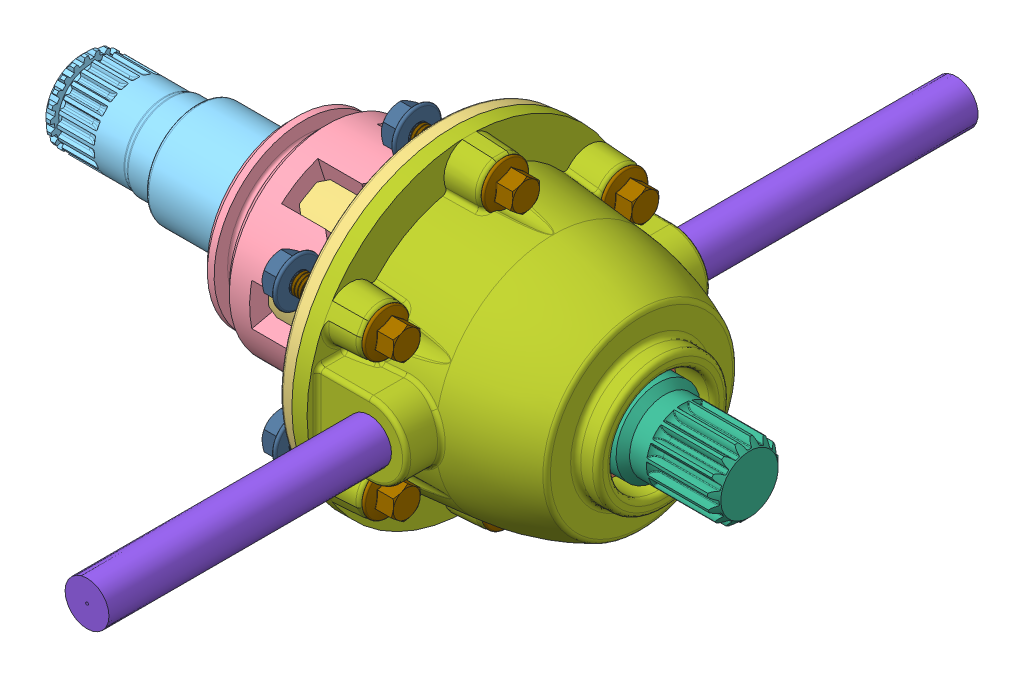
SolidWorks assembly complex assembly, configuration Default. Lengths in mm.
Overall size (197.45 149.08 257.22).
21 component instances, 10 part files, 47 mates.
Components (placement in the parent):
- gear-1: gear [Default] at (-34.573 11.9911 30.9445) x (1 0 0) z (0 0.244555 -0.969635) size (21.1 57.99 58.19)
- part 5c-1: part 5c [Default] at (51 0 0) x (0 -0.109301 0.994009) z (-1 0 0) size (44 44 5.35)
- Part6c-1: Part6c [Default] at (3.5 0.75 0) x (-1 0 0) z (0 -0.866025 -0.5) size (36 94 94)
- Part 1c-1: Part 1c [Default] at (-31.5 0.75 0) x (0 -0.477358 -0.878709) z (0 -0.878709 0.477358) size (58 34 58)
- part 3c-1: part 3c [Default] at (6.4991 0.75 0) x (-1 0 0) z (0 -0.038529 -0.999257) size (116.5 32 32)
- part 4-1: part 4 [Default] at (75.223 20.9631 25.3865) x (-1 0 0) z (0 -0.959651 -0.281194) size (58.1 57.76 58.19)
- complex-1: complex [Default] at origin size (62 133.62 96)
- straight miter gear_am-6: straight miter gear_am [Metric - Straight miter gear 2.75M12T 14.5PA 8FW ---12O13H120MD0.8N] at (20 0 28) x (0 0 -1) z (0.966628 0.256183 0) size (110.64 36.66 36.66)
- straight miter gear_am-7: straight miter gear_am [Metric - Straight miter gear 2.75M12T 14.5PA 8FW ---12O13H120MD0.8N] at (20 0 -28) x (0 0 1) z (-0.142818 0.989749 0) size (110.64 36.66 36.66)
- hex flange bolt small_iso-3: hex flange bolt small_iso [ISO 4162 - M6 x 25 x 25-S] at (21.3 -20.375 35.2905) x (-1 0 0) z (0 0.924225 0.381849) size (31.8 13.6 13.6)
- hex flange bolt small_iso-7: hex flange bolt small_iso [ISO 4162 - M6 x 25 x 25-S] at (21.3 40.75 0) x (-1 0 0) z (0 0.924225 0.381849) size (31.8 13.6 13.6)
- hex flange bolt small_iso-8: hex flange bolt small_iso [ISO 4162 - M6 x 25 x 25-S] at (21.3 20.375 -35.2905) x (-1 0 0) z (0 0.924225 0.381849) size (31.8 13.6 13.6)
- hex flange bolt small_iso-5: hex flange bolt small_iso [ISO 4162 - M6 x 25 x 25-S] at (21.3 -20.375 -35.2905) x (-1 0 0) z (0 0.924225 0.381849) size (31.8 13.6 13.6)
- hex flange bolt small_iso-2: hex flange bolt small_iso [ISO 4162 - M6 x 25 x 25-S] at (21.3 -40.75 0) x (-1 0 0) z (0 0.924225 0.381849) size (31.8 13.6 13.6)
- hex flange bolt small_iso-6: hex flange bolt small_iso [ISO 4162 - M6 x 25 x 25-S] at (21.3 20.375 35.2905) x (-1 0 0) z (0 0.924225 0.381849) size (31.8 13.6 13.6)
- hex flange nut gradea_iso-2: hex flange nut gradea_iso [ISO - 4161 - M6 - S] at (-16.5 20.375 35.2905) x (0 0 1) z (-1 0 0) size (14.2 14.2 6)
- hex flange nut gradea_iso-3: hex flange nut gradea_iso [ISO - 4161 - M6 - S] at (-16.5 40.75 0) x (0 0 1) z (-1 0 0) size (14.2 14.2 6)
- hex flange nut gradea_iso-5: hex flange nut gradea_iso [ISO - 4161 - M6 - S] at (-16.5 -40.75 0) x (0 0 1) z (-1 0 0) size (14.2 14.2 6)
- hex flange nut gradea_iso-6: hex flange nut gradea_iso [ISO - 4161 - M6 - S] at (-16.5 -20.375 -35.2905) x (0 0 1) z (-1 0 0) size (14.2 14.2 6)
- hex flange nut gradea_iso-7: hex flange nut gradea_iso [ISO - 4161 - M6 - S] at (-16.5 20.375 -35.2905) x (0 0 1) z (-1 0 0) size (14.2 14.2 6)
- hex flange nut gradea_iso-8: hex flange nut gradea_iso [ISO - 4161 - M6 - S] at (-16.5 -20.375 35.2905) x (0 0 1) z (-1 0 0) size (14.2 14.2 6)
Mates (geometry in assembly coordinates):
- Coincident6: coordinate: point of complex-1
- Concentric4: concentric aligned: cylinder of gear-1 through (-9.799 0.75 0) axis (1 0 0) radius 12.5; cylinder of Part6c-1 through (3.5 0.75 0) axis (1 0 0) radius 30.5
- Coincident8: coincident anti-aligned: plane of gear-1; plane of Part6c-1 through (-5 8 -12.5574) normal (1 0 0)
- Concentric5: concentric anti-aligned: cylinder of Part6c-1 through (3.5 0.75 0) axis (1 0 0) radius 34; cylinder of part 3c-1 through (-110.0009 0.75 0) axis (-1 0 0) radius 16
- Coincident9: coincident aligned: plane of part 3c-1 through (6.4991 0.75 0) normal (1 0 0); plane of gear-1 through (6.4991 0.75 0) normal (1 0 0)
- Coincident10: coincident aligned: line of gear-1 through (-8.5683 -8.2949 -7.886) axis (1 0 0); line of part 3c-1 through (-8.5683 -8.2949 -7.886) axis (1 0 0)
- Concentric6: concentric aligned: cylinder of Part6c-1 through (3.5 0.75 0) axis (1 0 0) radius 23.5; cylinder of Part 1c-1 through (-31.5 0.75 0) axis (1 0 0) radius 29
- Coincident11: coincident anti-aligned: plane of Part6c-1 through (-16.5 0.75 0) normal (-1 0 0); plane of Part 1c-1 through (-16.5 0.75 0) normal (1 0 0)
- Coincident12: coincident anti-aligned: plane of Part6c-1 through (-16.5 20.7042 -18.1888) normal (0 -0.673658 -0.739043); plane of Part 1c-1 through (-16.5 22.1823 -19.5361) normal (0 0.673658 0.739043)
- Concentric7: concentric anti-aligned: cylinder of part 5c-1 through (45.65 0 0) axis (1 0 0) radius 22; cylinder of part 4-1 through (50.449 0 0) axis (-1 0 0) radius 12.5
- Coincident13: coincident anti-aligned: plane of part 5c-1 through (45.65 0 0) normal (-1 0 0); plane of part 4-1 through (45.65 0 0) normal (1 0 0)
- Coincident14: coincident anti-aligned: plane of part 5c-1 through (51 0 0) normal (1 0 0); plane of complex-1 through (51 0 0) normal (-1 0 0)
- Concentric8: concentric anti-aligned: circle of complex-1; cylinder of straight miter gear_am-6 through (20 0 128.6116) axis (0 0 -1) radius 6.5
- Coincident16: coincident anti-aligned: plane of complex-1 through (20 0 28) normal (0 0 -1); plane of straight miter gear_am-6 through (20 0 28) normal (0 0 1)
- Concentric9: concentric anti-aligned: circle of complex-1; circle of straight miter gear_am-7
- Coincident18: coincident anti-aligned: plane of complex-1 through (20 0 -28) normal (0 0 1); plane of straight miter gear_am-7 through (20 0 -28) normal (0 0 -1)
- GearMate3: gear = 15 : 26.9979 mm: circle of part 4-1; circle of straight miter gear_am-6
- GearMate4: gear = 12 : 15 mm: circle of part 4-1; circle of straight miter gear_am-7
- Coincident19: coincident anti-aligned: plane of Part6c-1 through (-3.5 16.943 -29.4777) normal (1 0 0); plane of complex-1 through (0 0 0) normal (-1 0 0)
- GearMate5: gear = 14 : 12 mm: circle of straight miter gear_am-7; circle of gear-1
- GearMate6: gear = 14 : 12 mm: circle of straight miter gear_am-6; circle of gear-1
- Concentric16: concentric anti-aligned: cone of complex-1 through (4.5 -40.75 0) axis (-1 0 0); cylinder of hex flange bolt small_iso-2 through (21.3 -40.75 0) axis (1 0 0) radius 3
- Coincident22: coincident anti-aligned: plane of complex-1 through (14.5 0 0) normal (1 0 0); plane of hex flange bolt small_iso-2 through (14.5 -42.5137 4.2688) normal (-1 0 0)
- Concentric17: concentric anti-aligned: cone of complex-1 through (4.5 -20.375 35.2905) axis (-1 0 0); cylinder of hex flange bolt small_iso-3 through (21.3 -20.375 35.2905) axis (1 0 0) radius 3
- Coincident23: coincident anti-aligned: plane of complex-1 through (14.5 0 0) normal (1 0 0); plane of hex flange bolt small_iso-3 through (14.5 -22.1387 39.5593) normal (-1 0 0)
- Concentric18: concentric anti-aligned: cone of complex-1 through (4.5 -20.375 -35.2905) axis (-1 0 0); cylinder of hex flange bolt small_iso-5 through (21.3 -20.375 -35.2905) axis (1 0 0) radius 3
- Concentric19: concentric anti-aligned: cone of complex-1 through (4.5 20.375 35.2905) axis (-1 0 0); cylinder of hex flange bolt small_iso-6 through (21.3 20.375 35.2905) axis (1 0 0) radius 3
- Coincident25: coincident anti-aligned: plane of complex-1 through (14.5 0 0) normal (1 0 0); plane of hex flange bolt small_iso-6 through (14.5 18.6113 39.5593) normal (-1 0 0)
- Concentric20: concentric anti-aligned: cone of complex-1 through (4.5 40.75 0) axis (-1 0 0); cylinder of hex flange bolt small_iso-7 through (21.3 40.75 0) axis (1 0 0) radius 3
- Coincident26: coincident anti-aligned: plane of complex-1 through (14.5 0 0) normal (1 0 0); plane of hex flange bolt small_iso-7 through (14.5 38.9863 4.2688) normal (-1 0 0)
- Concentric21: concentric anti-aligned: cone of complex-1 through (4.5 20.375 -35.2905) axis (-1 0 0); cylinder of hex flange bolt small_iso-8 through (21.3 20.375 -35.2905) axis (1 0 0) radius 3
- Coincident27: coincident anti-aligned: plane of complex-1 through (14.5 0 0) normal (1 0 0); plane of hex flange bolt small_iso-8 through (14.5 18.6113 -31.0217) normal (-1 0 0)
- Coincident31: coincident anti-aligned: plane of Part6c-1 through (0 17.75 -29.4449) normal (1 0 0); plane of complex-1 through (0 0 0) normal (-1 0 0)
- Concentric28: concentric anti-aligned: circle of Part6c-1; circle of hex flange bolt small_iso-7
- Concentric31: concentric aligned: cone of hex flange bolt small_iso-6 through (-10.5 20.375 35.2905) axis (-1 0 0); cylinder of hex flange nut gradea_iso-2 through (8.5375 20.375 35.2905) axis (-1 0 0) radius 3
- Coincident34: coincident anti-aligned: plane of hex flange bolt small_iso-6 through (-10.5 20.375 35.2905) normal (-1 0 0); plane of hex flange nut gradea_iso-2 through (-10.5 26.1485 35.2905) normal (1 0 0)
- Concentric32: concentric aligned: cone of hex flange bolt small_iso-7 through (-10.5 40.75 0) axis (-1 0 0); cylinder of hex flange nut gradea_iso-3 through (8.5375 40.75 0) axis (-1 0 0) radius 3
- Coincident35: coincident anti-aligned: plane of hex flange bolt small_iso-7 through (-10.5 40.75 0) normal (-1 0 0); plane of hex flange nut gradea_iso-3 through (-10.5 46.5235 0) normal (1 0 0)
- Concentric33: concentric aligned: cone of hex flange bolt small_iso-2 through (-10.5 -40.75 0) axis (-1 0 0); cylinder of hex flange nut gradea_iso-5 through (8.5375 -40.75 0) axis (-1 0 0) radius 3
- Coincident36: coincident anti-aligned: plane of hex flange bolt small_iso-2 through (-10.5 -40.75 0) normal (-1 0 0); plane of hex flange nut gradea_iso-5 through (-10.5 -34.9765 0) normal (1 0 0)
- Concentric34: concentric aligned: cone of hex flange bolt small_iso-5 through (-10.5 -20.375 -35.2905) axis (-1 0 0); cylinder of hex flange nut gradea_iso-6 through (8.5375 -20.375 -35.2905) axis (-1 0 0) radius 3
- Coincident37: coincident anti-aligned: plane of hex flange bolt small_iso-5 through (-10.5 -20.375 -35.2905) normal (-1 0 0); plane of hex flange nut gradea_iso-6 through (-10.5 -14.6015 -35.2905) normal (1 0 0)
- Concentric35: concentric aligned: cone of hex flange bolt small_iso-8 through (-10.5 20.375 -35.2905) axis (-1 0 0); cylinder of hex flange nut gradea_iso-7 through (8.5375 20.375 -35.2905) axis (-1 0 0) radius 3
- Coincident38: coincident anti-aligned: plane of hex flange bolt small_iso-8 through (-10.5 20.375 -35.2905) normal (-1 0 0); plane of hex flange nut gradea_iso-7 through (-10.5 26.1485 -35.2905) normal (1 0 0)
- Concentric36: concentric aligned: cone of hex flange bolt small_iso-3 through (-10.5 -20.375 35.2905) axis (-1 0 0); cylinder of hex flange nut gradea_iso-8 through (8.5375 -20.375 35.2905) axis (-1 0 0) radius 3
- Coincident39: coincident anti-aligned: plane of hex flange bolt small_iso-3 through (-10.5 -20.375 35.2905) normal (-1 0 0); plane of hex flange nut gradea_iso-8 through (-10.5 -14.6015 35.2905) normal (1 0 0)
- Concentric37: concentric anti-aligned: circle of part 5c-1; circle of complex-1
